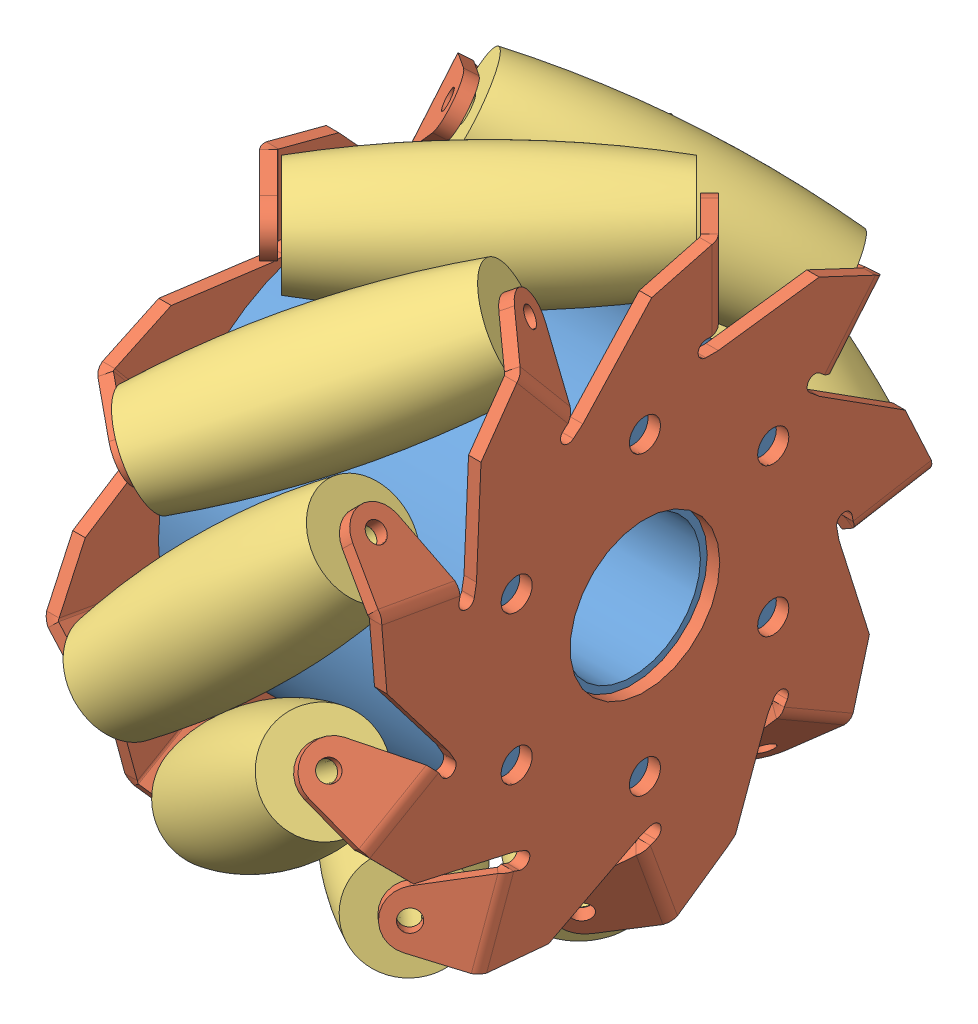
SolidWorks assembly Nexus 100mm Mecanum Wheel Right, configuration Default. Lengths in mm.
Overall size (52.68 128.61 128.42).
12 component instances, 3 part files, 23 mates.
Components (placement in the parent):
- Nexus 100mm Mecanum Wheel Core-1: Nexus 100mm Mecanum Wheel Core [Default] at (-63.153 17.1765 9.5188) size (46 60 60)
- Nexus 100mm Mecanum Wheel Right Plate-1: Nexus 100mm Mecanum Wheel Right Plate [Default] at (-17.2237 17.1765 9.5188) x (0 -0.5 0.866025) z (0 0.866025 0.5) size (93.83 10.6 94.33)
- Nexus 100mm Mecanum Wheel Right Plate-2: Nexus 100mm Mecanum Wheel Right Plate [Default] at (-63.0823 17.1765 9.5188) x (0 1 0) z (0 0 1) size (93.83 10.6 94.33)
- Nexus 100mm Mecanum Wheel Roller-1: Nexus 100mm Mecanum Wheel Roller [Default] at (-40.1575 48.0326 35.4043) x (0.675677 -0.208471 0.707107) z (-0.707107 -0.454519 0.541675) size (19.45 19.45 47)
- Nexus 100mm Mecanum Wheel Roller-2: Nexus 100mm Mecanum Wheel Roller [Default] at (-40.1575 24.1747 49.1822) x (0.507156 -0.378446 0.77432) z (-0.707107 -0.696364 0.122788) size (19.45 19.45 47)
- Nexus 100mm Mecanum Wheel Roller-3: Nexus 100mm Mecanum Wheel Roller [Default] at (-40.1575 -20.6691 23.2982) x (-0.490149 -0.509661 0.707107) z (-0.707107 -0.241845 -0.664463) size (19.45 19.45 47)
- Nexus 100mm Mecanum Wheel Roller-4: Nexus 100mm Mecanum Wheel Roller [Default] at (-40.1575 -2.9577 44.4011) x (0.630602 -0.319908 -0.707107) z (0.707107 0.612372 0.353553) size (19.45 19.45 47)
- Nexus 100mm Mecanum Wheel Roller-5: Nexus 100mm Mecanum Wheel Roller [Default] at (-40.1575 -2.9655 -25.3591) x (0.630602 0.319908 -0.707107) z (0.707107 -0.612372 0.353553) size (19.45 19.45 47)
- Nexus 100mm Mecanum Wheel Roller-6: Nexus 100mm Mecanum Wheel Roller [Default] at (-40.1575 -20.6722 -4.2522) x (0.699603 0.102742 -0.707107) z (0.707107 -0.241845 0.664463) size (19.45 19.45 47)
- Nexus 100mm Mecanum Wheel Roller-7: Nexus 100mm Mecanum Wheel Roller [Default] at (-40.1575 57.4525 9.5143) x (0.707107 0 0.707107) z (-0.707107 0 0.707107) size (19.45 19.45 47)
- Nexus 100mm Mecanum Wheel Roller-8: Nexus 100mm Mecanum Wheel Roller [Default] at (-40.1575 48.0268 -16.3736) x (0.675677 0.208471 0.707107) z (-0.707107 0.454519 0.541675) size (19.45 19.45 47)
- Nexus 100mm Mecanum Wheel Roller-9: Nexus 100mm Mecanum Wheel Roller [Default] at (-40.1575 24.1659 -30.1462) x (0.55468 0.438555 0.707107) z (-0.707107 0.696364 0.122788) size (19.45 19.45 47)
Mates (geometry in assembly coordinates):
- Concentric1: concentric aligned: circle of Nexus 100mm Mecanum Wheel Core-1; circle of Nexus 100mm Mecanum Wheel Right Plate-1
- Coincident1: coincident anti-aligned: plane of Nexus 100mm Mecanum Wheel Core-1 through (-17.153 17.1765 9.5188) normal (1 0 0); plane of Nexus 100mm Mecanum Wheel Right Plate-1 through (-17.153 23.6765 -1.7396) normal (-1 0 0)
- Coincident2: coincident anti-aligned: plane of Nexus 100mm Mecanum Wheel Core-1 through (-63.153 17.1765 9.5188) normal (-1 0 0); plane of Nexus 100mm Mecanum Wheel Right Plate-2 through (-63.153 4.1765 9.5188) normal (1 0 0)
- Concentric2: concentric anti-aligned: circle of Nexus 100mm Mecanum Wheel Core-1; circle of Nexus 100mm Mecanum Wheel Right Plate-2
- Distance1: distance = 0.5 mm anti-aligned: plane of Nexus 100mm Mecanum Wheel Roller-1 through (-56.7745 37.3514 48.1336) normal (-0.707107 -0.454519 0.541675); plane of Nexus 100mm Mecanum Wheel Right Plate-2 through (-63.7388 42.6292 44.3941) normal (0.707107 0.454519 -0.541675)
- Concentric3: concentric anti-aligned: circle of Nexus 100mm Mecanum Wheel Right Plate-2; circle of Nexus 100mm Mecanum Wheel Roller-1
- Concentric4: concentric anti-aligned: circle of Nexus 100mm Mecanum Wheel Right Plate-2; circle of Nexus 100mm Mecanum Wheel Right Plate-1
- Distance2: distance = 0.5 mm anti-aligned: plane of Nexus 100mm Mecanum Wheel Roller-7 through (-56.7745 57.4525 26.1313) normal (-0.707107 0 0.707107); plane of Nexus 100mm Mecanum Wheel Right Plate-2 through (-63.7388 59.0918 19.8741) normal (0.707107 0 -0.707107)
- Concentric5: concentric anti-aligned: circle of Nexus 100mm Mecanum Wheel Right Plate-2; circle of Nexus 100mm Mecanum Wheel Roller-7
- Concentric6: concentric anti-aligned: circle of Nexus 100mm Mecanum Wheel Right Plate-2; circle of Nexus 100mm Mecanum Wheel Roller-8
- Distance3: distance = 0.5 mm anti-aligned: plane of Nexus 100mm Mecanum Wheel Roller-8 through (-56.7745 58.708 -3.6443) normal (-0.707107 0.454519 0.541675); plane of Nexus 100mm Mecanum Wheel Right Plate-2 through (-63.7388 55.9418 -9.4912) normal (0.707107 -0.454519 -0.541675)
- Concentric7: concentric anti-aligned: circle of Nexus 100mm Mecanum Wheel Right Plate-2; circle of Nexus 100mm Mecanum Wheel Roller-2
- Distance4: distance = 0.5 mm anti-aligned: plane of Nexus 100mm Mecanum Wheel Right Plate-2 through (-63.7388 14.257 52.5955) normal (0.707107 0.696364 -0.122788); plane of Nexus 100mm Mecanum Wheel Roller-2 through (-56.7745 7.8102 52.0677) normal (-0.707107 -0.696364 0.122788)
- Concentric8: concentric anti-aligned: circle of Nexus 100mm Mecanum Wheel Right Plate-2; circle of Nexus 100mm Mecanum Wheel Roller-3
- Distance5: distance = 0.5 mm anti-aligned: plane of Nexus 100mm Mecanum Wheel Roller-3 through (-56.7745 -26.3525 7.6833) normal (-0.707107 -0.241845 -0.664463); plane of Nexus 100mm Mecanum Wheel Right Plate-2 through (-63.7388 -25.7528 14.1238) normal (0.707107 0.241845 0.664463)
- Concentric9: concentric aligned: circle of Nexus 100mm Mecanum Wheel Right Plate-2; circle of Nexus 100mm Mecanum Wheel Roller-4
- Distance6: distance = 0.5 mm anti-aligned: plane of Nexus 100mm Mecanum Wheel Roller-4 through (-56.7745 -17.3484 36.0926) normal (-0.707107 -0.612372 -0.353553); plane of Nexus 100mm Mecanum Wheel Right Plate-2 through (-63.7388 -12.7492 40.6409) normal (0.707107 0.612372 0.353553)
- Concentric10: concentric aligned: circle of Nexus 100mm Mecanum Wheel Right Plate-2; circle of Nexus 100mm Mecanum Wheel Roller-6
- Distance7: distance = 0.5 mm anti-aligned: plane of Nexus 100mm Mecanum Wheel Right Plate-2 through (-63.7388 -18.6694 -14.548) normal (0.707107 -0.241845 0.664463); plane of Nexus 100mm Mecanum Wheel Roller-6 through (-56.7745 -14.9888 -19.8671) normal (-0.707107 0.241845 -0.664463)
- Concentric11: concentric aligned: circle of Nexus 100mm Mecanum Wheel Right Plate-2; circle of Nexus 100mm Mecanum Wheel Roller-5
- Distance8: distance = 0.5 mm anti-aligned: plane of Nexus 100mm Mecanum Wheel Right Plate-2 through (-63.7388 5.1868 -31.9587) normal (0.707107 -0.612372 0.353553); plane of Nexus 100mm Mecanum Wheel Roller-5 through (-56.7745 11.4253 -33.6676) normal (-0.707107 0.612372 -0.353553)
- Concentric12: concentric anti-aligned: circle of Nexus 100mm Mecanum Wheel Right Plate-2; circle of Nexus 100mm Mecanum Wheel Roller-9
- Distance9: distance = 0.5 mm anti-aligned: plane of Nexus 100mm Mecanum Wheel Right Plate-2 through (-63.7388 34.653 -29.9616) normal (0.707107 -0.696364 -0.122788); plane of Nexus 100mm Mecanum Wheel Roller-9 through (-56.7745 40.5305 -27.2607) normal (-0.707107 0.696364 0.122788)
